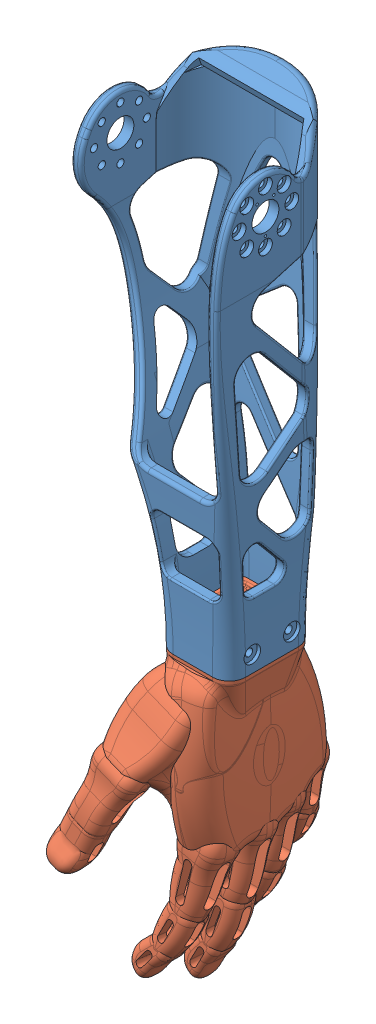
SolidWorks assembly forearm, configuration left. Lengths in mm.
Overall size (55.2 228.71 65.03).
2 component instances, 2 part files, 6 mates.
Components (placement in the parent):
- forearm-1: forearm [MX28-left] at (-29.588 58.3543 8.5922) size (55.2 137.66 53.14)
- hand-1: hand [left_fake_human_like_hand] at (-19.088 -61.6457 4.5922) x (0 0 -1) z (0 -1 0) size (64.5 37.73 100.68)
Mates (geometry in assembly coordinates):
- Concentric1: concentric anti-aligned: cylinder of hand-1 through (-30.088 -56.6457 -1.4078) axis (1 0 0) radius 1.1; cylinder of forearm-1 through (-34.088 -56.6457 -1.4078) axis (-1 0 0) radius 1.1
- Concentric2: concentric anti-aligned: cylinder of hand-1 through (-30.088 -56.6457 10.5922) axis (1 0 0) radius 1.1; cylinder of forearm-1 through (-34.088 -56.6457 10.5922) axis (-1 0 0) radius 1.1
- Coincident1: coincident aligned: plane of forearm-1 through (-19.088 58.3543 8.5922) normal (1 0 0); plane of hand-1
- Coincident2: coincident aligned: plane of forearm-1 through (-40.1492 58.3543 8.5922) normal (1 0 0); plane of hand-1
- Concentric5: concentric aligned: cylinder of hand-1 through (-51.1492 -56.6457 10.5922) axis (1 0 0) radius 1.1; cylinder of forearm-1 through (-25.088 -56.6457 10.5922) axis (1 0 0) radius 1.1
- Concentric6: concentric aligned: cylinder of forearm-1 through (-25.088 -56.6457 -1.4078) axis (1 0 0) radius 1.1; cylinder of hand-1 through (-51.1492 -56.6457 -1.4078) axis (1 0 0) radius 1.1
